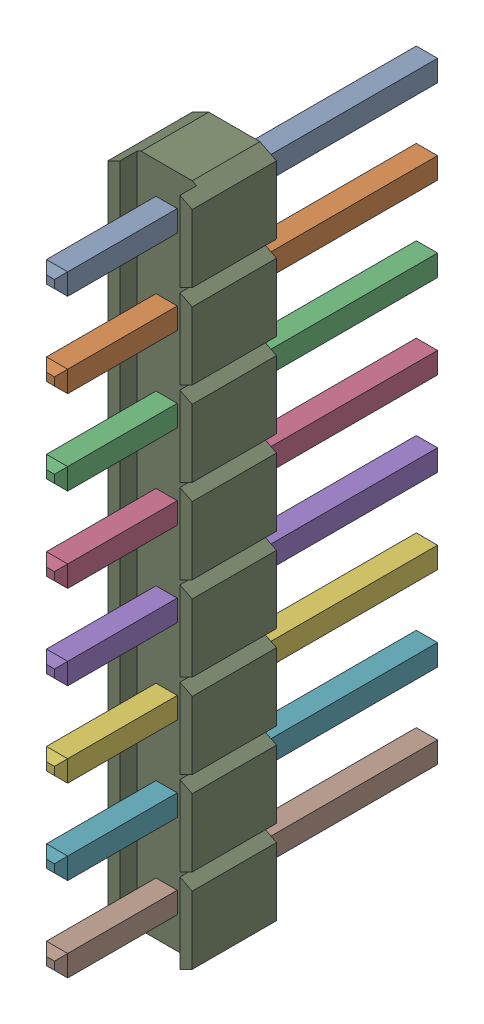
SolidWorks assembly 1-10, configuration ﾃﾞﾌｫﾙﾄ. Lengths in mm.
Overall size (2.54 20.32 11.54).
9 component instances, 9 part files, 0 mates.
Components (placement in the parent):
- Header8_2.54mm_RGB255-1: Header8_2.54mm_RGB255 [ﾃﾞﾌｫﾙﾄ] at (21.3613 10.3123 -1.2168) x (0 -1 0) z (1 0 0) size (0.64 11.54 0.64)
- Header8_2.54mm_RGB255-11-1: Header8_2.54mm_RGB255-11 [ﾃﾞﾌｫﾙﾄ] at (21.3613 10.3123 -1.2168) x (0 -1 0) z (1 0 0) size (0.64 11.54 0.64)
- Header8_2.54mm_RGB255-12-1: Header8_2.54mm_RGB255-12 [ﾃﾞﾌｫﾙﾄ] at (21.3613 10.3123 -1.2168) x (0 -1 0) z (1 0 0) size (0.64 11.54 0.64)
- Header8_2.54mm_RGB255-13-1: Header8_2.54mm_RGB255-13 [ﾃﾞﾌｫﾙﾄ] at (21.3613 10.3123 -1.2168) x (0 -1 0) z (1 0 0) size (0.64 11.54 0.64)
- Header8_2.54mm_RGB255-14-1: Header8_2.54mm_RGB255-14 [ﾃﾞﾌｫﾙﾄ] at (21.3613 10.3123 -1.2168) x (0 -1 0) z (1 0 0) size (0.64 11.54 0.64)
- Header8_2.54mm_RGB255-15-1: Header8_2.54mm_RGB255-15 [ﾃﾞﾌｫﾙﾄ] at (21.3613 10.3123 -1.2168) x (0 -1 0) z (1 0 0) size (0.64 11.54 0.64)
- Header8_2.54mm_RGB255-16-1: Header8_2.54mm_RGB255-16 [ﾃﾞﾌｫﾙﾄ] at (21.3613 10.3123 -1.2168) x (0 -1 0) z (1 0 0) size (0.64 11.54 0.64)
- Header8_2.54mm_RGB255-17-1: Header8_2.54mm_RGB255-17 [ﾃﾞﾌｫﾙﾄ] at (21.3613 10.3123 -1.2168) x (0 -1 0) z (1 0 0) size (0.64 11.54 0.64)
- Header8_2.54mm_RGB255-18-1: Header8_2.54mm_RGB255-18 [ﾃﾞﾌｫﾙﾄ] at (21.3613 10.3123 -1.2168) x (0 -1 0) z (1 0 0) size (20.32 2.54 2.54)
